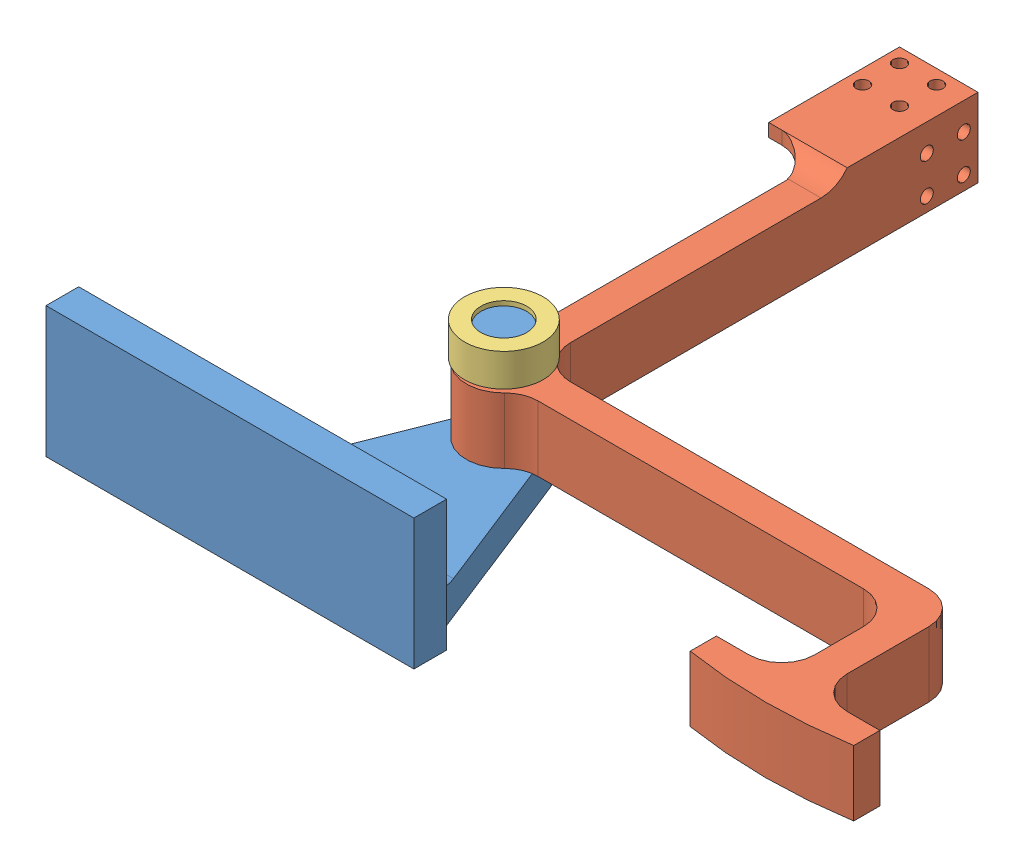
SolidWorks assembly RotorTestRig, configuration Default. Lengths in mm.
Overall size (230 41.36 205).
3 component instances, 3 part files, 4 mates.
Components (placement in the parent):
- Base-1: Base [Default] at origin size (113.27 40 76)
- Lever-1: Lever [Default] at (0 10 0) size (174 24.54 190)
- Cap-1: Cap [Default] at (0 31.3621 0) x (0.999285 0 -0.037807) z (0.037807 0 0.999285) size (24 10 24)
Mates (geometry in assembly coordinates):
- Concentric1: concentric aligned: cylinder of Base-1 through (0 40 0) axis (0 -1 0) radius 7; cylinder of Lever-1 through (0 30 0) axis (0 -1 0) radius 7.5
- Coincident1: coincident anti-aligned: plane of Base-1 through (0 10 0) normal (0 1 0); plane of Lever-1 through (0 10 0) normal (0 -1 0)
- Parallel1: parallel: line of Lever-1 through (15.4029 30 5) axis (1 0 0)
- Concentric2: concentric aligned: cylinder of Base-1 through (0 40 0) axis (0 -1 0) radius 7; cylinder of Cap-1 through (0 41.3621 0) axis (0 -1 0) radius 7
